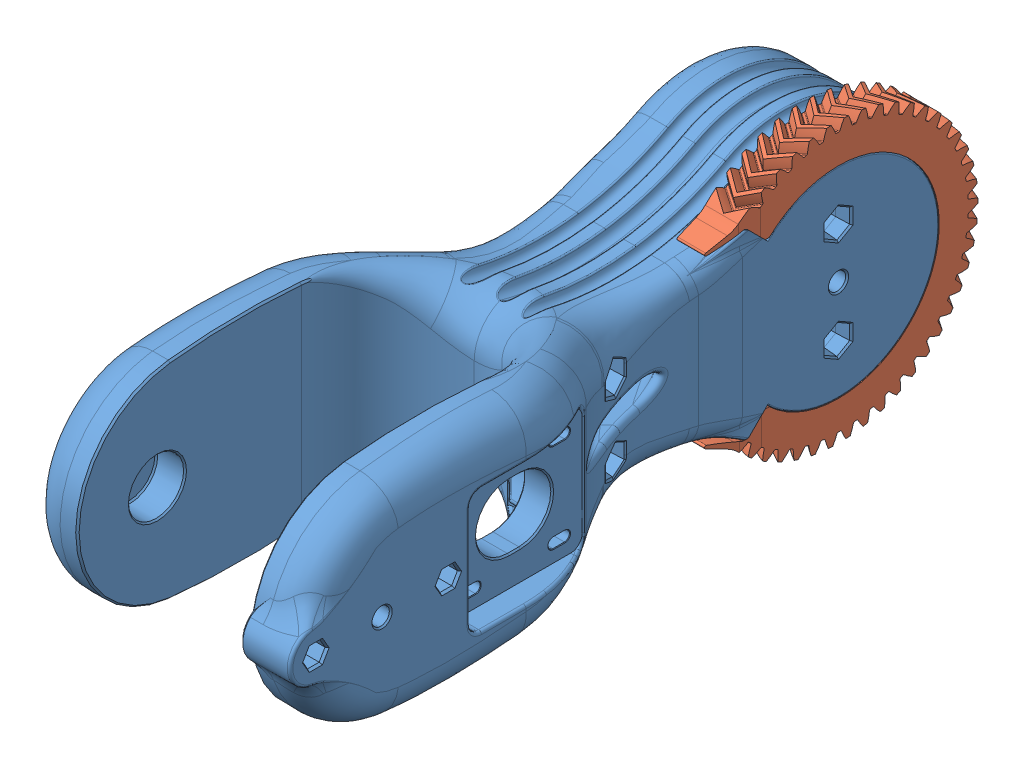
SolidWorks assembly 4.1 Structure, configuration Domyślna. Lengths in mm.
Overall size (113.83 97.55 280.56).
2 component instances, 2 part files, 4 mates.
Components (placement in the parent):
- 4.1.1 Arm1-1: 4.1.1 Arm1 [Domyślna] at origin size (113.83 88.77 280.56)
- 4.1.3 ISO - RH Helical gear 1.5M 50T 37HA 20PA 6FW ---50A75H50L70.0N-2: 4.1.3 ISO - RH Helical gear 1.5M 50T 37HA 20PA 6FW ---50A75H50L70.0N [ISO - RH Helical gear 1.5M 50T 37HA 20PA 6FW ---50A75H50L70.0N] at (14.5 0 0) x (1 0 0) z (0 -0.00576 0.999983) size (12.27 97.02 92.76)
Mates (geometry in assembly coordinates):
- Wspólnie3: coordinate: point of 4.1.1 Arm1-1; point of assembly
- Wspólnie4: coincident anti-aligned: plane of 4.1.1 Arm1-1 through (14.5 0 0) normal (1 0 0); plane of 4.1.3 ISO - RH Helical gear 1.5M 50T 37HA 20PA 6FW ---50A75H50L70.0N-2 through (14.5 0 0) normal (-1 0 0)
- Wspólnie5: coincident anti-aligned: plane of 4.1.1 Arm1-1 through (14.5 30 30) normal (0 0.707107 -0.707107); plane of 4.1.3 ISO - RH Helical gear 1.5M 50T 37HA 20PA 6FW ---50A75H50L70.0N-2 through (20.5 0 0) normal (0 -0.707107 0.707107)
- Koncentryczne1: concentric anti-aligned: cylinder of 4.1.1 Arm1-1 through (14.5 0 0) axis (1 0 0) radius 35; cylinder of 4.1.3 ISO - RH Helical gear 1.5M 50T 37HA 20PA 6FW ---50A75H50L70.0N-2 through (77 0 0) axis (-1 0 0) radius 35
